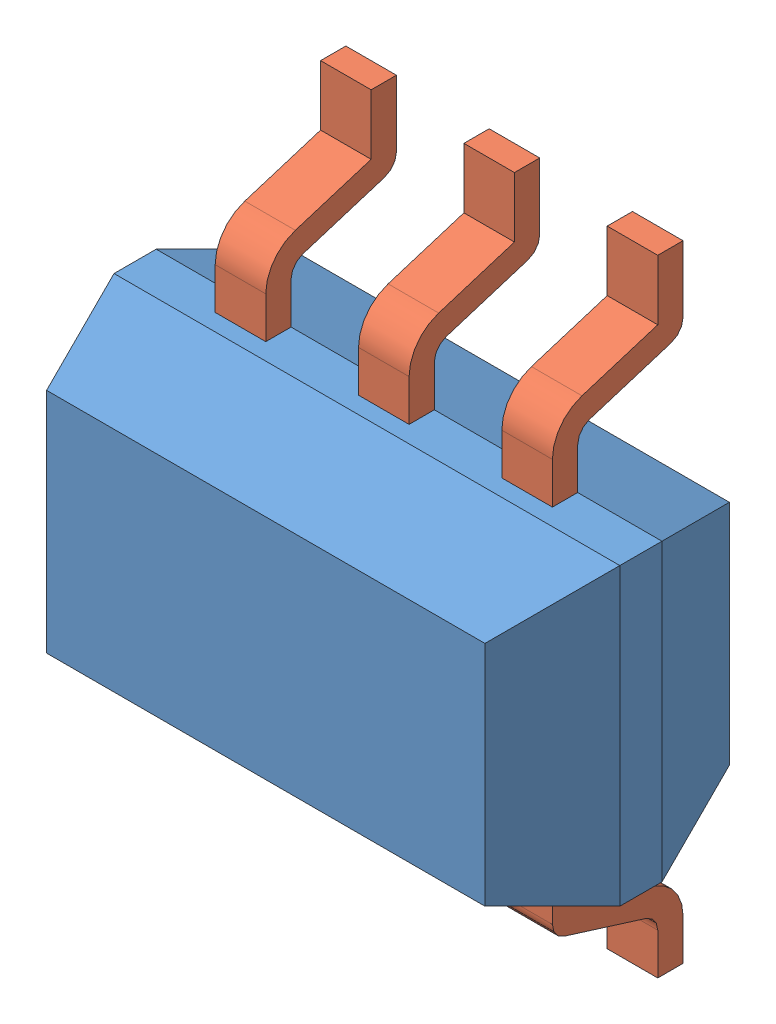
SolidWorks assembly Assemblage4, configuration Défaut. Lengths in mm.
Overall size (3 3.71 1.47).
7 component instances, 2 part files, 18 mates.
Components (placement in the parent):
- U3_boitier-1: U3_boitier [Défaut] at (-11.8964 30.2254 -0.725) size (3 1.75 1.45)
- U3_Pin-1: U3_Pin [Défaut] at (-10.5464 30.2254 0.025) x (0 -1 0) z (1 0 0) size (0.98 0.78 0.3)
- U3_Pin-2: U3_Pin [Défaut] at (-11.3964 30.2254 0.025) x (0 -1 0) z (1 0 0) size (0.98 0.78 0.3)
- U3_Pin-5: U3_Pin [Défaut] at (-9.6964 30.2254 0.025) x (0 -1 0) z (1 0 0) size (0.98 0.78 0.3)
- U3_Pin-6: U3_Pin [Défaut] at (-10.2464 32.9566 -0.75) x (0 -1 0) z (-1 0 0) size (0.98 0.78 0.3)
- U3_Pin-7: U3_Pin [Défaut] at (-11.0964 32.9566 -0.75) x (0 -1 0) z (-1 0 0) size (0.98 0.78 0.3)
- U3_Pin-8: U3_Pin [Défaut] at (-9.3964 32.9566 -0.75) x (0 -1 0) z (-1 0 0) size (0.98 0.78 0.3)
Mates (geometry in assembly coordinates):
- Coïncidente1: coincident anti-aligned: plane of U3_boitier-1 through (-11.8964 30.2254 0.725) normal (0 -1 0); plane of U3_Pin-1 through (-10.2464 30.2254 -0.125) normal (0 1 0)
- Coïncidente2: coincident anti-aligned: line of U3_boitier-1 through (-11.8964 30.2254 -0.125) axis (1 0 0); line of U3_Pin-1 through (-10.2464 30.2254 -0.125) axis (-1 0 0)
- Coïncidente3: coincident: moEndPointRef_w of U3_boitier-1; moEndPointRef_w of U3_Pin-1
- Coïncidente4: coincident aligned: plane of U3_Pin-1 through (-10.2464 29.2442 -0.75) normal (0 -1 0); plane of U3_Pin-2 through (-11.0964 29.2442 -0.75) normal (0 -1 0)
- Coïncidente5: coincident anti-aligned: line of U3_boitier-1 through (-11.8964 30.2254 -0.125) axis (1 0 0); line of U3_Pin-2 through (-11.0964 30.2254 -0.125) axis (-1 0 0)
- Distance1: distance = 0.55 mm anti-aligned: plane of U3_Pin-2 through (-11.0964 29.8317 -0.075) normal (1 0 0); plane of U3_Pin-1 through (-10.5464 29.8317 -0.075) normal (-1 0 0)
- Coïncidente11: coincident aligned: plane of U3_Pin-1 through (-10.2464 29.2442 -0.75) normal (0 -1 0); plane of U3_Pin-5 through (-9.3964 29.2442 -0.75) normal (0 -1 0)
- Coïncidente12: coincident anti-aligned: line of U3_boitier-1 through (-11.8964 30.2254 -0.125) axis (1 0 0); line of U3_Pin-5 through (-9.3964 30.2254 -0.125) axis (-1 0 0)
- Distance4: distance = 0.55 mm: line of U3_Pin-5 through (-9.6964 29.7362 -0.0452) axis (0 -0.297593 -0.954693); line of U3_Pin-1 through (-10.2464 29.7362 -0.0452) axis (0 -0.297593 -0.954693)
- Coïncidente14: coincident anti-aligned: line of U3_boitier-1 through (-8.8964 31.9754 -0.125) axis (-1 0 0); line of U3_Pin-6 through (-10.5464 31.9754 -0.125) axis (1 0 0)
- Coïncidente15: coincident anti-aligned: plane of U3_boitier-1 through (-11.8964 31.9754 0.725) normal (0 1 0); plane of U3_Pin-6 through (-10.5464 31.9754 0.025) normal (0 -1 0)
- Coïncidente16: coincident: moEndPointRef_w of U3_boitier-1; moEndPointRef_w of U3_Pin-6
- Coïncidente17: coincident aligned: plane of U3_Pin-6 through (-10.5464 32.9566 -0.6) normal (0 1 0); plane of U3_Pin-7 through (-11.3964 32.9566 -0.6) normal (0 1 0)
- Coïncidente18: coincident anti-aligned: line of U3_boitier-1 through (-8.8964 31.9754 -0.125) axis (-1 0 0); line of U3_Pin-7 through (-11.3964 31.9754 -0.125) axis (1 0 0)
- Distance5: distance = 0.55 mm: line of U3_Pin-6 through (-10.5464 32.4595 -0.1506) axis (0 0.297593 -0.954693); line of U3_Pin-7 through (-11.0964 32.4595 -0.1506) axis (0 0.297593 -0.954693)
- Coïncidente20: coincident aligned: plane of U3_Pin-6 through (-10.5464 32.9566 -0.6) normal (0 1 0); plane of U3_Pin-8 through (-9.6964 32.9566 -0.6) normal (0 1 0)
- Coïncidente21: coincident anti-aligned: line of U3_boitier-1 through (-8.8964 31.9754 -0.125) axis (-1 0 0); line of U3_Pin-8 through (-9.6964 31.9754 -0.125) axis (1 0 0)
- Distance6: distance = 0.55 mm: line of U3_Pin-8 through (-9.6964 32.4595 -0.1506) axis (0 0.297593 -0.954693); line of U3_Pin-6 through (-10.2464 32.4595 -0.1506) axis (0 0.297593 -0.954693)
